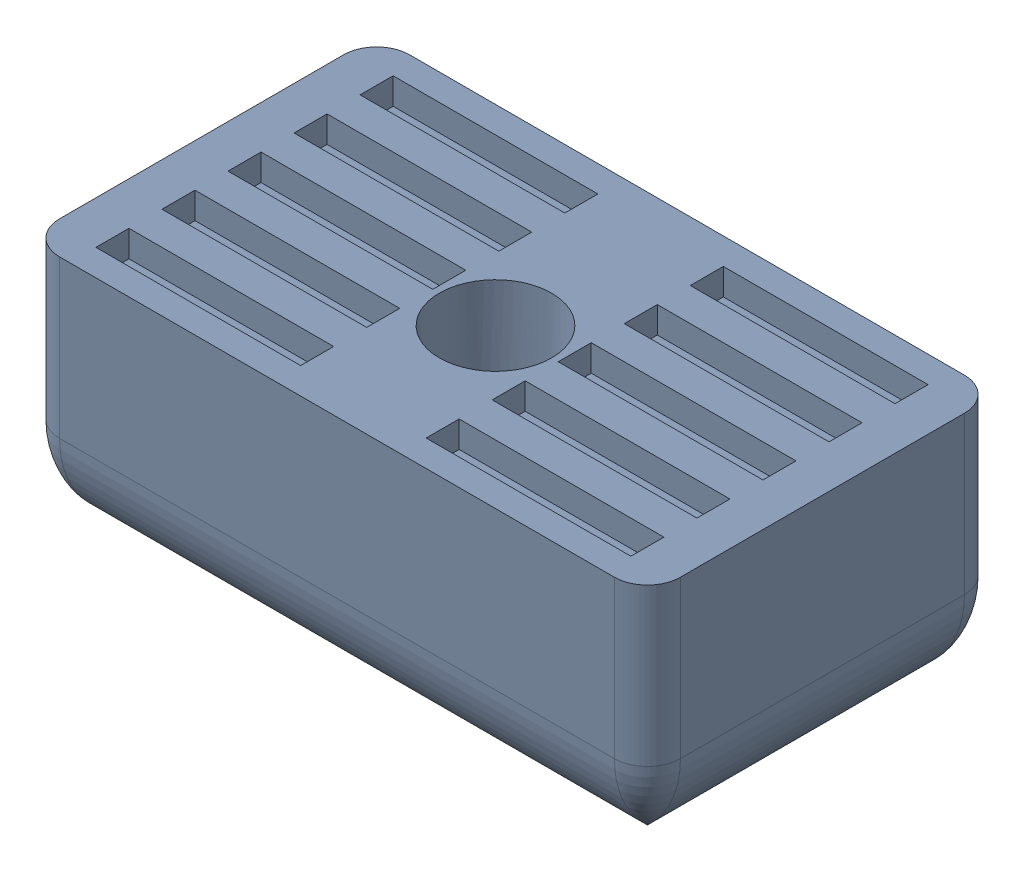
SolidWorks assembly Belt Clip, configuration Default. Lengths in mm.
Overall size (18.8 7 10.6).
2 component instances, 2 part files, 0 mates.
Components (placement in the parent):
- Belt Clip-1: Belt Clip [Default] at origin size (18.8 7 10.6)
- M3 Threaded Insert (1)-1: M3 Threaded Insert (1) [Default] at (-82.7703 134.942 -16.1565) x (1 0 0) z (0 -1 0) size (5 5 3.85)
